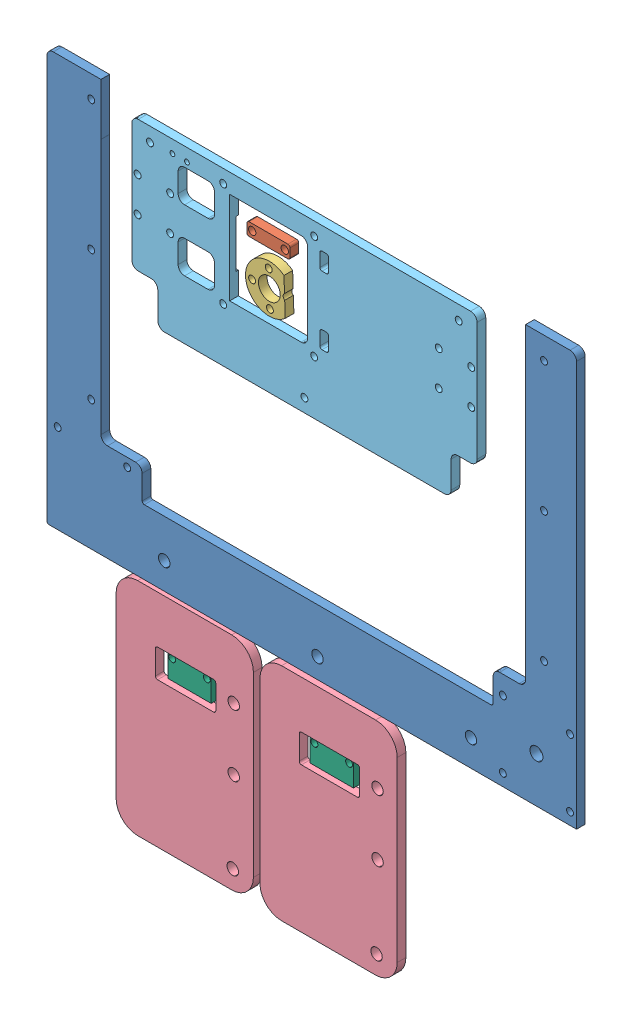
SolidWorks assembly Z AND Y FRAME PLUS SMALL ONES2, configuration Default. Lengths in mm.
Overall size (255.05 344.12 6).
8 component instances, 6 part files, 11 mates.
Components (placement in the parent):
- Z Frame-1: Z Frame [Valor predeterminado] at (-101.6268 37.5207 24.9892) size (250 190 4)
- Hotend bracket-2: Hotend bracket [Valor predeterminado] at (-58.817 25.7523 -108.3764) size (19.93 5.9 4)
- Z nut atachment to X Bridge-2: Z nut atachment to X Bridge [Valor predeterminado] at (219.3796 158.5045 24.9892) x (0.034129 -0.999417 0) z (0 0 1) size (22 18.05 4)
- Small foot2-1: Small foot2 [Default] at (24.4377 163.2189 24.9892) size (63.38 101.97 4)
- Small foot2-2: Small foot2 [Default] at (-41.9465 164.041 24.9892) size (63.38 101.97 4)
- Bed Support2-2: Bed Support2 [Default] at (-162.4717 -4.7041 24.9892) size (159.38 135.83 4)
- BELT HOLDER-1: BELT HOLDER [Default] at (-149.1455 -133.606 22.9892) size (20.01 11 4)
- BELT HOLDER-2: BELT HOLDER [Default] at (-83.4915 -134.6139 22.9892) size (20.01 11 4)
Mates (geometry in assembly coordinates):
- Distance37: distance = 3 mm anti-aligned: plane of Small foot2-1 through (-84.0259 -103.2862 28.9892) normal (-1 0 0); plane of Small foot2-2 through (-87.0259 -102.4641 28.9892) normal (1 0 0)
- Coincident1: coincident aligned: plane of Z Frame-1 through (-179.3832 86.4051 28.9892) normal (0 0 1); plane of Small foot2-1 through (24.4377 163.2189 28.9892) normal (0 0 1)
- Coincident2: coincident aligned: plane of Z Frame-1 through (-179.3832 86.4051 28.9892) normal (0 0 1); plane of Small foot2-2 through (-41.9465 164.041 28.9892) normal (0 0 1)
- Coincident3: coincident aligned: plane of Z Frame-1 through (-179.3832 86.4051 28.9892) normal (0 0 1); plane of Hotend bracket-2 through (-58.817 25.7523 28.9892) normal (0 0 1)
- Coincident4: coincident aligned: plane of Z Frame-1 through (-179.3832 86.4051 28.9892) normal (0 0 1); plane of Hotend bracket-2 through (-58.817 25.7523 28.9892) normal (0 0 1)
- Parallel1: parallel anti-aligned: plane of Z Frame-1 through (-157.3832 -41.5949 28.9892) normal (1 0 0); plane of Small foot2-2 through (-150.4101 -102.4641 28.9892) normal (-1 0 0)
- Coincident5: coincident aligned: plane of Z Frame-1 through (-179.3832 86.4051 28.9892) normal (0 0 1); plane of Bed Support2-2 through (-162.4717 -4.7041 28.9892) normal (0 0 1)
- Coincident6: coincident aligned: plane of Z Frame-1 through (-179.3832 86.4051 28.9892) normal (0 0 1); plane of Hotend bracket-2 through (-58.817 25.7523 28.9892) normal (0 0 1)
- Coincident7: coincident aligned: plane of Z Frame-1 through (-179.3832 86.4051 28.9892) normal (0 0 1); plane of Z nut atachment to X Bridge-2 through (-79.6727 44.5853 28.9892) normal (0 0 1)
- Coincident8: coincident aligned: plane of Z Frame-1 through (-179.3832 86.4051 28.9892) normal (0 0 1); plane of Small foot2-1 through (24.4377 163.2189 28.9892) normal (0 0 1)
- Coincident9: coincident aligned: plane of Z Frame-1 through (-179.3832 86.4051 28.9892) normal (0 0 1); plane of Small foot2-2 through (-41.9465 164.041 28.9892) normal (0 0 1)
